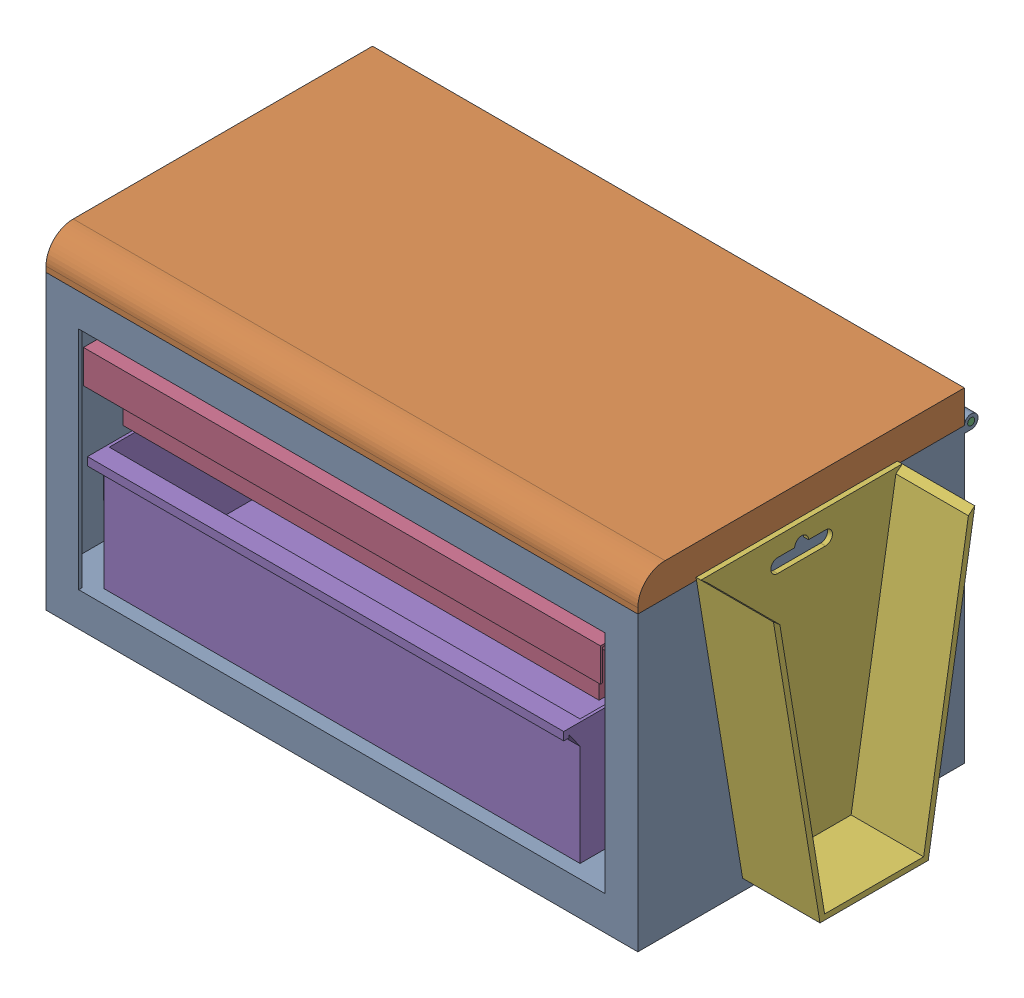
SolidWorks assembly SP-A0101-AA-Tool Box and Wrench Holder, configuration Default. Lengths in mm.
Overall size (312.36 151.77 166.37).
6 component instances, 6 part files, 13 mates.
Components (placement in the parent):
- SP-00001-AA-Box-1: SP-00001-AA-Box [Default] at (-32.56 103.5596 146.5347) size (276.23 139.7 158.75)
- SP-00002-AA-Lid-1: SP-00002-AA-Lid [Default] at (-32.56 103.5596 146.5347) size (276.23 18.41 158.75)
- SP-00005-AA-Hinge Pin-1: SP-00005-AA-Hinge Pin [Default] at (-34.084 103.5596 -7.5163) size (276.23 3.3 3.3)
- SP-00003-AA-Upper Drawer-1: SP-00003-AA-Upper Drawer [Default] at (104.0285 50.7911 139.1687) size (241.3 31.18 135.89)
- SP-00004-AA-lower drawer-1: SP-00004-AA-lower drawer [Default] at (104.0285 -10.7404 84.5587) size (222.25 57.15 134.62)
- SP-50001-AA-Wrench Mount-1: SP-50001-AA-Wrench Mount [Default] at (242.141 104.8434 73.9212) x (0 0 -1) z (0 -1 0) size (93.98 36.13 132.49)
Mates (geometry in assembly coordinates):
- Coincident1: coincident aligned: plane of SP-00001-AA-Box-1 through (242.141 -32.9654 148.0587) normal (1 0 0); plane of SP-00002-AA-Lid-1 through (242.141 118.7996 146.5347) normal (1 0 0)
- Concentric1: concentric anti-aligned: cylinder of SP-00001-AA-Box-1 through (159.591 103.5596 -7.5163) axis (1 0 0) radius 1.651; cylinder of SP-00005-AA-Hinge Pin-1 through (242.141 103.5596 -7.5163) axis (-1 0 0) radius 1.651
- Concentric2: concentric aligned: cylinder of SP-00002-AA-Lid-1 through (154.8285 103.5596 -7.5163) axis (-1 0 0) radius 1.651; cylinder of SP-00005-AA-Hinge Pin-1 through (242.141 103.5596 -7.5163) axis (-1 0 0) radius 1.651
- Coincident2: coincident aligned: plane of SP-00001-AA-Box-1 through (-34.084 -32.9654 148.0587) normal (-1 0 0); plane of SP-00005-AA-Hinge Pin-1 through (-34.084 103.5596 -7.5163) normal (-1 0 0)
- LimitAngle1: limit planar angle = 0 rad anti-aligned: plane of SP-00002-AA-Lid-1 through (-32.56 103.5596 146.5347) normal (0 -1 0); plane of SP-00001-AA-Box-1 through (-32.56 103.5596 146.5347) normal (0 1 0)
- Coincident4: coincident anti-aligned: plane of SP-00001-AA-Box-1 through (215.1535 69.2696 179.8596) normal (-1 0 0); plane of SP-00003-AA-Upper Drawer-1 through (215.1535 53.3311 139.1687) normal (1 0 0)
- Distance3: distance = 6.35 mm anti-aligned: plane of SP-00001-AA-Box-1 through (-32.56 88.3196 146.5347) normal (0 -1 0); plane of SP-00003-AA-Upper Drawer-1 through (-16.6215 81.9696 139.1687) normal (0 1 0)
- LimitDistance1: limit distance = 0 mm aligned: plane of SP-00003-AA-Upper Drawer-1 through (-16.6215 81.9696 148.0587) normal (0 0 1); plane of SP-00001-AA-Box-1 through (-34.084 -32.9654 148.0587) normal (0 0 1)
- Coincident7: coincident anti-aligned: plane of SP-00001-AA-Box-1 through (215.1535 18.4696 179.8596) normal (-1 0 0); plane of SP-00004-AA-lower drawer-1 through (215.1535 46.4096 148.0587) normal (1 0 0)
- Distance4: distance = 6.35 mm anti-aligned: plane of SP-00001-AA-Box-1 through (-32.56 -17.0904 146.5347) normal (0 1 0); plane of SP-00004-AA-lower drawer-1 through (104.0285 -10.7404 84.5587) normal (0 -1 0)
- LimitDistance2: limit distance = 0 mm aligned: plane of SP-00001-AA-Box-1 through (-34.084 -32.9654 148.0587) normal (0 0 1); plane of SP-00004-AA-lower drawer-1 through (215.1535 46.4096 148.0587) normal (0 0 1)
- Coincident8: coincident anti-aligned: plane of SP-00001-AA-Box-1 through (242.141 -32.9654 148.0587) normal (1 0 0); plane of SP-50001-AA-Wrench Mount-1 through (242.141 104.8434 73.9212) normal (-1 0 0)
- Parallel2: parallel aligned: plane of SP-00001-AA-Box-1 through (-32.56 -32.9654 146.5347) normal (0 -1 0); plane of SP-50001-AA-Wrench Mount-1 through (244.427 -27.643 99.1879) normal (0 -1 0)
